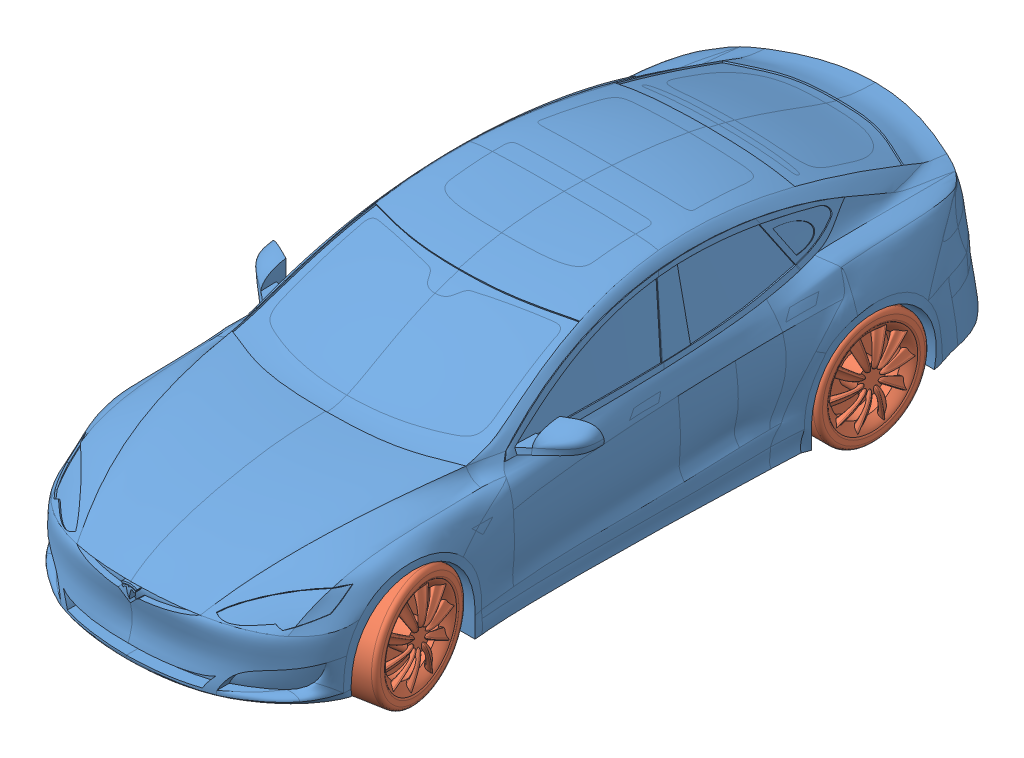
SolidWorks assembly Model S Assembly, configuration Default. Lengths in mm.
Overall size (5212.42 1655.86 5010.67).
5 component instances, 2 part files, 0 mates.
Components (placement in the parent):
- Tesla Model S Body-1: Tesla Model S Body [Default] at (-4.3435 685.841 -370.7377) size (2261.89 1291.55 4996.29)
- Model S Wheels-1: Model S Wheels [Default] at (-135.9279 -2465.0421 940.7452) x (0.983255 0 -0.182236) z (-0.025709 0.989999 -0.138715) size (301.46 727.68 727.68)
- Model S Wheels-2: Model S Wheels [Default] at (1.6901 802.4686 -3246.3873) x (1 0 0) z (0 -0.080454 0.996758) size (301.46 727.68 727.68)
- Model S Wheels-3: Model S Wheels [Default] at (-7.6652 1704.9145 -2000.2571) x (-1 0 0) z (0 -0.973095 -0.230404) size (301.46 727.68 727.68)
- Model S Wheels-4: Model S Wheels [Default] at (28.5839 -263.9248 -637.1748) x (-1 0 0) z (0 -0.539062 0.842266) size (301.46 727.68 727.68)
